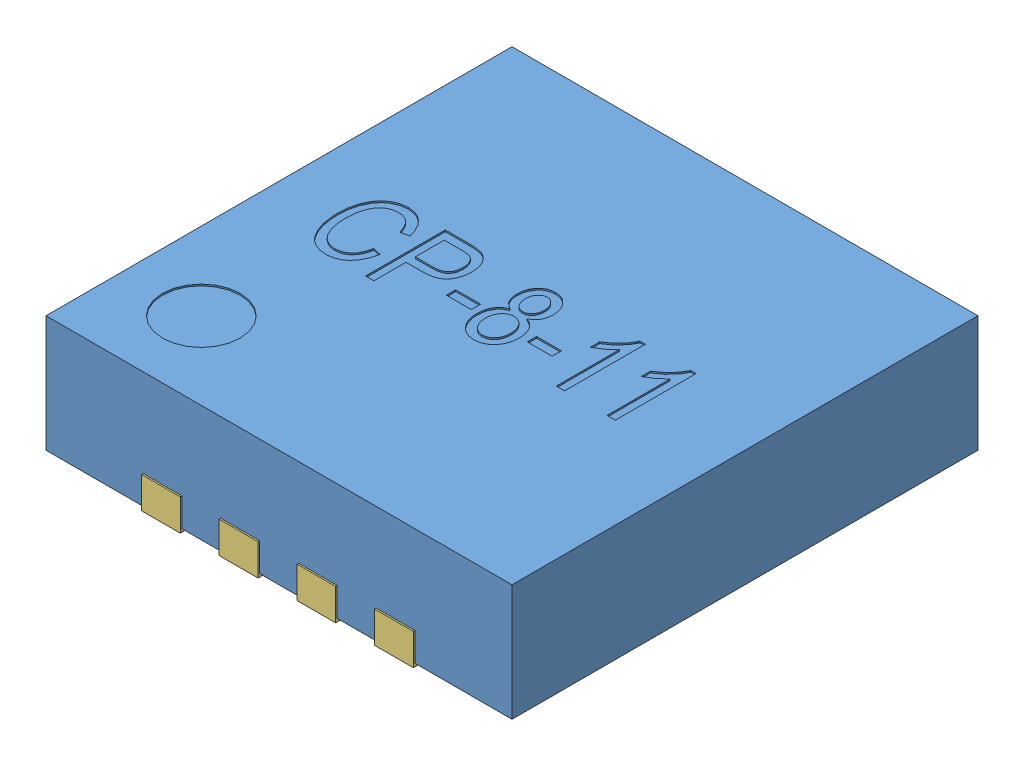
SolidWorks assembly CP-8-11, configuration Default. Lengths in mm.
Overall size (3 0.77 3.02).
10 component instances, 3 part files, 9 mates.
Components (placement in the parent):
- Body-2: Body [Default] at (0 0.02 0) size (3 0.75 3)
- EP-5: EP [Default] at (0 0.203 0) x (-1 0 0) z (0 0 1) size (2.34 0.2 1.6)
- P-33: P [Default] at (0.75 0 1.3675) size (0.25 0.2 0.41)
- P-34: P [Default] at (0.25 0 1.3675) size (0.25 0.2 0.41)
- P-35: P [Default] at (-0.25 0 1.3675) size (0.25 0.2 0.41)
- P-36: P [Default] at (-0.75 0 1.3675) size (0.25 0.2 0.41)
- P-37: P [Default] at (0.75 0 -1.3675) x (-1 0 0) z (0 0 -1) size (0.25 0.2 0.41)
- P-38: P [Default] at (0.25 0 -1.3675) x (-1 0 0) z (0 0 -1) size (0.25 0.2 0.41)
- P-39: P [Default] at (-0.25 0 -1.3675) x (-1 0 0) z (0 0 -1) size (0.25 0.2 0.41)
- P-40: P [Default] at (-0.75 0 -1.3675) x (-1 0 0) z (0 0 -1) size (0.25 0.2 0.41)
Mates (geometry in assembly coordinates):
- Coincident14: coincident aligned: plane of Body-2 through (0 0.02 0) normal (0 0 1); plane of assembly through (0 0 0) normal (0 0 1)
- Coincident15: coincident aligned: plane of Body-2 through (0 0.02 0) normal (1 0 0); plane of assembly through (0 0 0) normal (1 0 0)
- Distance1: distance = 0.02 mm: plane of assembly through (0 0 0) normal (0 1 0); plane of Body-2 through (0 0.02 0) normal (0 -1 0)
- Coincident22: coincident anti-aligned: plane of EP-5 through (0 0 0) normal (0 -1 0)
- Coincident23: coincident aligned: plane of Body-2 through (0 0.02 0) normal (0 0 1); plane of EP-5 through (0 0.203 0) normal (0 0 1)
- Coincident24: coincident anti-aligned: plane of EP-5 through (0 0.203 0) normal (-1 0 0)
- Coincident25: coincident anti-aligned: plane of P-33 through (0.75 0 1.225) normal (0 -1 0)
- Distance4: distance = 0.75 mm aligned: plane of P-33 through (0.75 0 1.3675) normal (1 0 0)
- Distance5: distance = 0.01 mm aligned: plane of Body-2 through (-1.5 0.77 1.5) normal (0 0 1); plane of P-33 through (0.625 0.203 1.51) normal (0 0 1)
